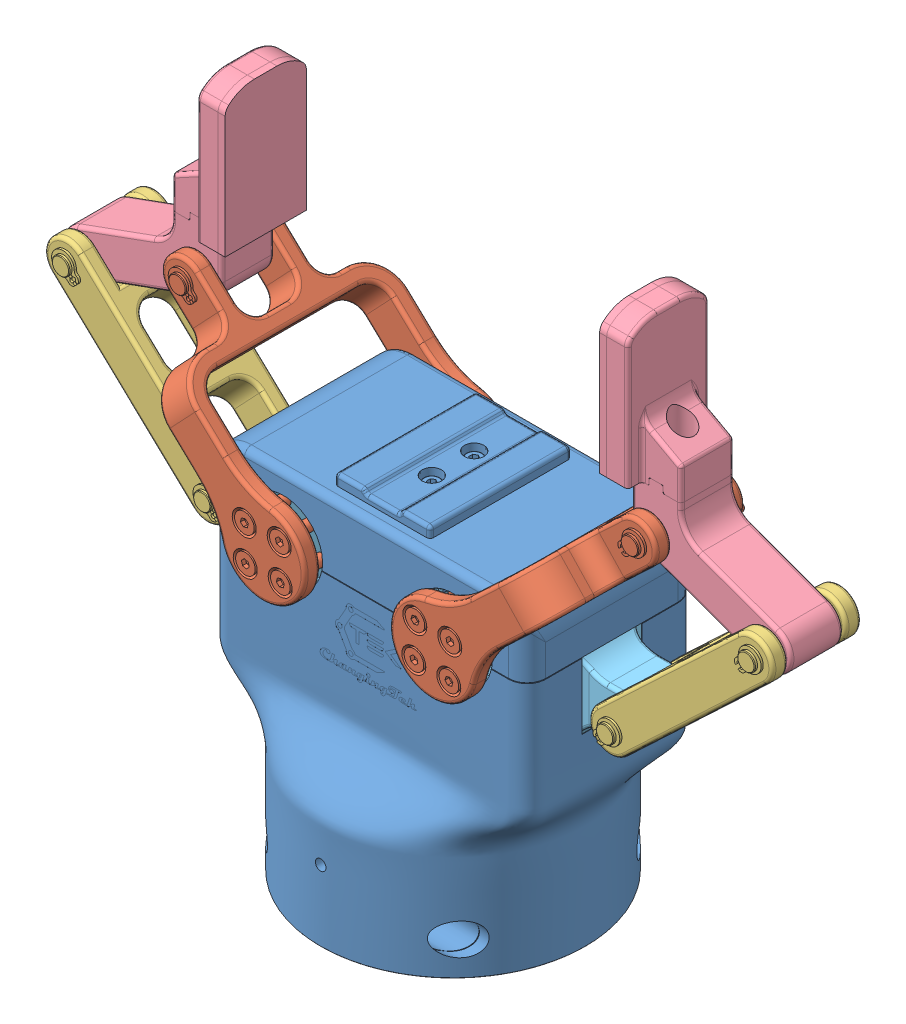
SolidWorks assembly CTM2F.00_两指模块化手(内嵌控制器版)-20220719-00, configuration 默认. Lengths in mm.
Overall size (208.02 169.01 76.09).
11 component instances, 5 part files, 10 mates.
Components (placement in the parent):
- CTM2F.00_两指模块化手(内嵌控制器版)-20220719-01-1: CTM2F.00_两指模块化手(内嵌控制器版)-20220719-01 [默认] at origin size (90.98 100.76 76.09)
- CTM2F.02.02_手指组件-20220719-00-1: CTM2F.02.02_手指组件-20220719-00 [默认] at (-23.9 65 0) size (110.01 131 60) (flexible)
  - CTM2F.02.02_手指组件-20220719-01-1: CTM2F.02.02_手指组件-20220719-01 [默认] at (-0.1 15.75 0) x (0.98269 0.185258 0) z (0 0 1) size (50.31 62.51 60)
  - CTM2F.02.02_手指组件-20220719-02-1: CTM2F.02.02_手指组件-20220719-02 [默认] at (-2.8943 21.6558 0) x (0.98269 0.185258 0) z (0 0 1) size (44.31 56.51 28.2)
  - CTM2F.02.02_手指组件-20220719-03-1: CTM2F.02.02_手指组件-20220719-03 [默认] at (-7.7858 8.9931 0) size (50 68.5 23)
  - CTM2F.02.01_模块架组件-20220719-1: CTM2F.02.01_模块架组件-20220719 [默认] x (-1 0 0) z (0 0 -1) size (69 54 42)
- CTM2F.02.02_手指组件-20220719-00-2: CTM2F.02.02_手指组件-20220719-00 [默认] at (23.9 65 0) x (-1 0 0) z (0 0 -1) size (110.01 131 60) (flexible)
  - CTM2F.02.02_手指组件-20220719-01-1: CTM2F.02.02_手指组件-20220719-01 [默认] at (-0.1 15.75 0) x (0.98269 0.185258 0) z (0 0 1) size (50.31 62.51 60)
  - CTM2F.02.02_手指组件-20220719-02-1: CTM2F.02.02_手指组件-20220719-02 [默认] at (-2.8943 21.6558 0) x (0.98269 0.185258 0) z (0 0 1) size (44.31 56.51 28.2)
  - CTM2F.02.02_手指组件-20220719-03-1: CTM2F.02.02_手指组件-20220719-03 [默认] at (-7.7858 8.9931 0) size (50 68.5 23)
  - CTM2F.02.01_模块架组件-20220719-1: CTM2F.02.01_模块架组件-20220719 [默认] x (-1 0 0) z (0 0 -1) size (69 54 42)
Mates (geometry in assembly coordinates):
- 重合1: coincident aligned: plane of CTM2F.00_两指模块化手(内嵌控制器版)-20220719-01-1 through (0 0 0) normal (1 0 0); plane of assembly through (0 0 0) normal (1 0 0)
- 重合2: coincident aligned: plane of CTM2F.00_两指模块化手(内嵌控制器版)-20220719-01-1 through (0 0 0) normal (0 1 0); plane of assembly through (0 0 0) normal (0 1 0)
- 重合3: coincident aligned: plane of CTM2F.00_两指模块化手(内嵌控制器版)-20220719-01-1 through (0 0 0) normal (0 0 1); plane of assembly through (0 0 0) normal (0 0 1)
- 重合4: coincident aligned: plane of CTM2F.02.02_手指组件-20220719-00-1 through (-23.9 65 0) normal (0 0 1); plane of assembly through (0 0 0) normal (0 0 1)
- 同心1: concentric anti-aligned: cylinder of CTM2F.00_两指模块化手(内嵌控制器版)-20220719-01-1 through (-24 80.75 -38.0431) axis (0 0 1) radius 11; cylinder of CTM2F.02.02_手指组件-20220719-00-1/CTM2F.02.02_手指组件-20220719-01-1 through (-24 80.75 30) axis (0 0 -1) radius 12
- 同心2: concentric anti-aligned: cylinder of CTM2F.00_两指模块化手(内嵌控制器版)-20220719-01-1 through (-24 -0.001 0) axis (0 1 0) radius 3; cylinder of CTM2F.02.02_手指组件-20220719-00-1/CTM2F.02.01_模块架组件-20220719-1 through (-24 92.001 0) axis (0 -1 0) radius 4.5
- 重合5: coincident anti-aligned: plane of CTM2F.00_两指模块化手(内嵌控制器版)-20220719-01-1 through (0 38 0) normal (0 1 0); plane of CTM2F.02.02_手指组件-20220719-00-1/CTM2F.02.01_模块架组件-20220719-1 through (-23.9 38 0) normal (0 -1 0)
- 同心3: concentric aligned: cylinder of CTM2F.00_两指模块化手(内嵌控制器版)-20220719-01-1 through (24 80.75 -38.0431) axis (0 0 1) radius 11; cylinder of CTM2F.02.02_手指组件-20220719-00-2/CTM2F.02.02_手指组件-20220719-01-1 through (24 80.75 -30) axis (0 0 1) radius 12
- LimitDistance1: limit distance = 53 mm aligned: plane of CTM2F.02.02_手指组件-20220719-00-1/CTM2F.02.02_手指组件-20220719-03-1 through (-53 149.2492 0) normal (1 0 0); plane of assembly through (0 0 0) normal (1 0 0)
- 对称1: symmetric aligned: plane of CTM2F.02.02_手指组件-20220719-00-1/CTM2F.02.02_手指组件-20220719-03-1 through (-53 149.2492 0) normal (1 0 0); plane of CTM2F.02.02_手指组件-20220719-00-2/CTM2F.02.02_手指组件-20220719-03-1 through (53 149.2492 0) normal (-1 0 0); plane of assembly through (0 0 0) normal (1 0 0)
